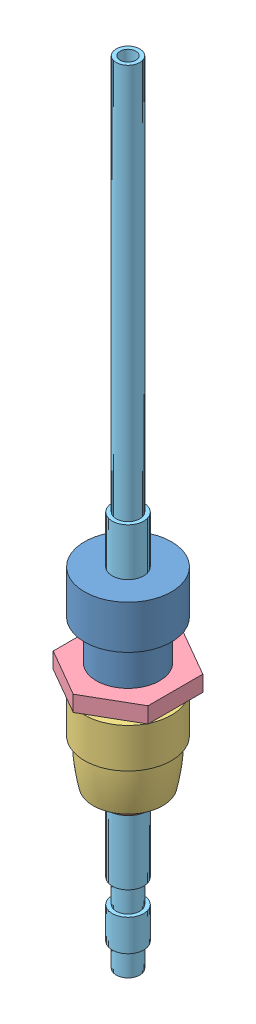
SolidWorks assembly Цанга с большой иглой, configuration По умолчанию. Lengths in mm.
Overall size (12 100 13.86).
6 component instances, 5 part files, 6 mates.
Components (placement in the parent):
- Цанговый зажим-1: Цанговый зажим [По умолчанию] x (1 0 0) z (0 0 -1) size (12 25.5 13.86)
  - втулка-1: втулка [По умолчанию] at origin size (11 20 11)
  - цанга-1: цанга [По умолчанию] at (0 10 0) size (6 15.5 6)
  - прижимная гайка-1: прижимная гайка [По умолчанию] at (0 13.5 0) x (-1 0 0) z (0 0 -1) size (11 10.5 11)
  - фиксирующая гайка-1: фиксирующая гайка [По умолчанию] at (0 12.5 0) x (1 0 0) z (0 -1 0) size (12 13.86 2)
- Игла без соска большая 1-2: Игла без соска большая 1 [По умолчанию] at (0 -44 0) size (4 100 4)
Mates (geometry in assembly coordinates):
- Совпадение1: coincident aligned: plane of Цанговый зажим-1/втулка-1 through (5.5 0 0) normal (0 1 0); plane of assembly through (0 0 0) normal (0 1 0)
- Совпадение2: coincident anti-aligned: plane of Цанговый зажим-1/втулка-1 through (0 0 0) normal (0 0 -1); plane of assembly through (0 0 0) normal (0 0 1)
- Совпадение3: coincident aligned: plane of Цанговый зажим-1/втулка-1; plane of assembly through (0 0 0) normal (1 0 0)
- Концентричный1: concentric anti-aligned: cylinder of Цанговый зажим-1/цанга-1 through (0 -25.5 0) axis (0 1 0) radius 2; cylinder of Игла без соска большая 1-2 through (0 56 0) axis (0 -1 0) radius 2
- Совпадение8: coincident: plane of Цанговый зажим-1/прижимная гайка-1 through (0 -24 0) normal (0 -1 0); point of Игла без соска большая 1-2
- Параллельность1: parallel aligned: plane of Игла без соска большая 1-2 through (0 -44 0) normal (0 0 1); plane of assembly
